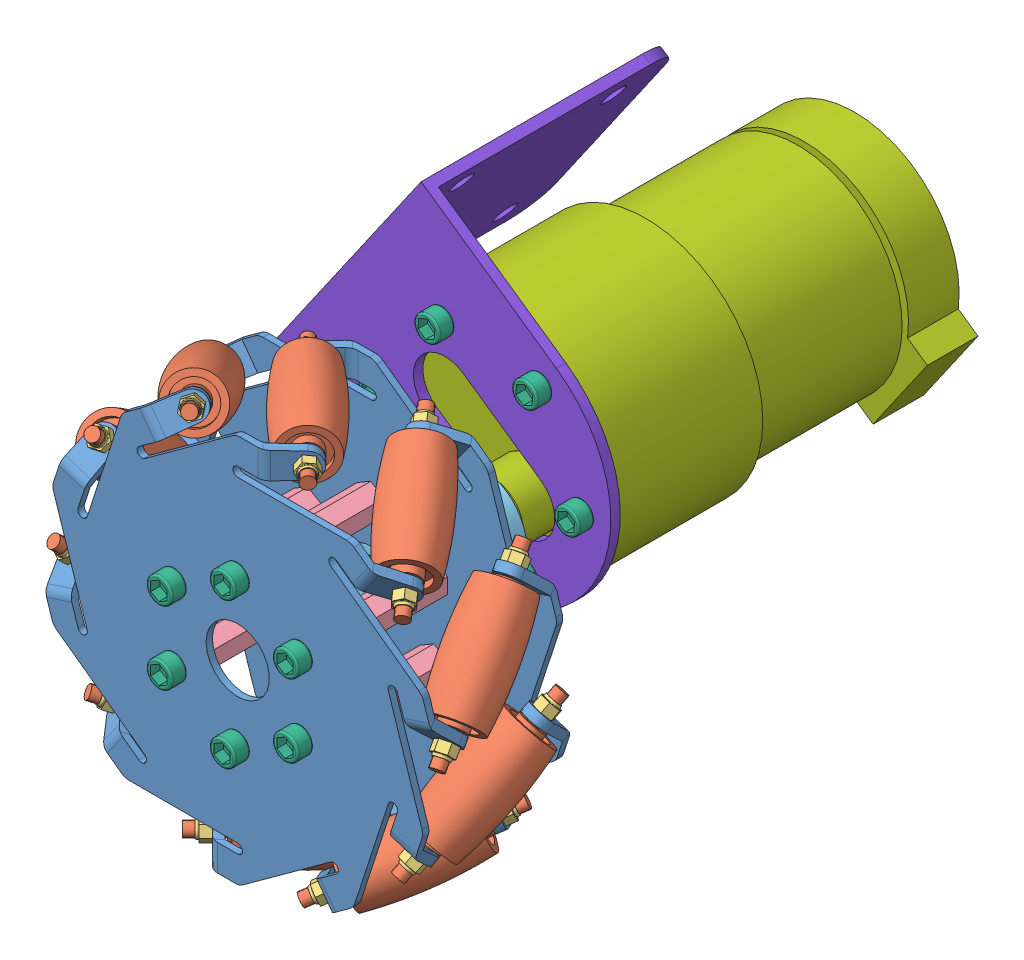
SolidWorks assembly 左前轮, configuration 默认. Lengths in mm.
Overall size (75.09 69.56 106.55).
61 component instances, 8 part files, 9 mates.
Components (placement in the parent):
- 麦克纳姆轮装配（2）-1: 麦克纳姆轮装配（2） [默认] at (10.9105 -1.19 -0.8307) size (73.19 68.37 28.98)
  - 麦克纳姆轮（2）-1: 麦克纳姆轮（2） [默认] at (4.7846 1.1432 62.959) size (62.96 61.4 5.95)
  - 麦克纳姆轮（2）-2: 麦克纳姆轮（2） [默认] at (4.7846 1.1432 85.0986) x (-1 0 0) z (0 0 -1) size (62.96 61.4 5.95)
  - 辊子-1: 辊子 [默认] at (-6.5323 29.7426 62.712) x (0.707107 0 0.707107) z (-0.707107 0 0.707107) size (28 9.23 9.23)
  - 辊子-2: 辊子 [默认] at (-21.1917 17.6211 62.6991) x (0.572061 0.415627 0.707107) z (-0.707107 -0.186947 0.681946) size (28 9.23 9.23)
  - 辊子-3: 辊子 [默认] at (-25.9161 -0.7943 62.6991) x (0.218508 0.672499 0.707107) z (-0.650722 -0.439573 0.619142) size (28 9.23 9.23)
  - 辊子-4: 辊子 [默认] at (-25.9121 3.0685 85.3457) x (0.218508 -0.672499 -0.707107) z (0.395342 -0.60148 0.694209) size (28 9.23 9.23)
  - 辊子-6: 辊子 [默认] at (-21.1812 -15.3423 85.3457) x (0.572061 -0.415627 -0.707107) z (0.647393 -0.300533 0.700401) size (28 9.23 9.23)
  - 辊子-7: 辊子 [默认] at (-6.5323 -27.4561 85.3457) x (0.707107 0 -0.707107) z (0.705301 0.071414 0.705301) size (28 9.23 9.23)
  - 辊子-8: 辊子 [默认] at (12.4393 -28.646 85.3457) x (0.572061 0.415627 -0.707107) z (0.714443 0.170963 0.678486) size (28 9.23 9.23)
  - 辊子-9: 辊子 [默认] at (35.4853 3.0808 62.6991) x (-0.218508 -0.672499 0.707107) z (-0.954109 -0.00482 -0.29942) size (28 9.23 9.23)
  - 辊子-10: 辊子 [默认] at (28.4831 20.7562 62.6991) x (0.218508 -0.672499 0.707107) z (-0.771684 0.324444 0.547028) size (28 9.23 9.23)
  - 辊子-11: 辊子 [默认] at (12.4289 30.9401 62.6991) x (0.572061 -0.415627 0.707107) z (-0.689 0.22422 0.689206) size (28 9.23 9.23)
  - M2【螺母】-1: M2【螺母】 [默认] at (-5.0722 29.3326 82.6238) x (0.808299 -0.139279 -0.572061) z (-0.572061 -0.415627 -0.707107) size (2.79 3.22 1.95)
  - M2【螺母】-2: M2【螺母】 [默认] at (13.3795 29.7426 82.6238) x (0.572061 -0.587785 -0.572061) z (-0.707107 0 -0.707107) size (2.79 3.22 1.95)
  - M2【螺母】-3: M2【螺母】 [默认] at (28.5483 19.2286 82.6238) x (0.117316 -0.811778 -0.572061) z (-0.572061 0.415627 -0.707107) size (2.79 3.22 1.95)
  - M2【螺母】-4: M2【螺母】 [默认] at (34.6402 1.8066 82.6238) x (-0.38224 -0.725698 -0.572061) z (-0.218508 0.672499 -0.707107) size (2.79 3.22 1.95)
  - M2【螺母】-5: M2【螺母】 [默认] at (29.3282 -15.8687 82.6238) x (-0.735794 -0.362427 -0.572061) z (0.218508 0.672499 -0.707107) size (2.79 3.22 1.95)
  - M2【螺母】-6: M2【螺母】 [默认] at (14.6414 -27.0461 82.6238) x (-0.808299 0.139279 -0.572061) z (0.572061 0.415627 -0.707107) size (2.79 3.22 1.95)
  - M2【螺母】-7: M2【螺母】 [默认] at (-3.8104 -27.4561 82.6238) x (-0.572061 0.587785 -0.572061) z (0.707107 0 -0.707107) size (2.79 3.22 1.95)
  - M2【螺母】-8: M2【螺母】 [默认] at (-18.9791 -16.9422 82.6238) x (-0.117316 0.811778 -0.572061) z (0.572061 -0.415627 -0.707107) size (2.79 3.22 1.95)
  - M2【螺母】-9: M2【螺母】 [默认] at (-25.071 0.4798 82.6238) x (0.38224 0.725698 -0.572061) z (0.218508 -0.672499 -0.707107) size (2.79 3.22 1.95)
  - M2【螺母】-10: M2【螺母】 [默认] at (-19.759 18.1552 82.6238) x (0.735794 0.362427 -0.572061) z (-0.218508 -0.672499 -0.707107) size (2.79 3.22 1.95)
  - M2【螺母】-11: M2【螺母】 [默认] at (-19.759 -15.8687 65.4339) x (0.972031 0.086079 0.218508) z (-0.218508 0.672499 0.707107) size (2.79 3.22 1.95)
  - M2【螺母】-12: M2【螺母】 [默认] at (-5.0722 -27.0461 65.4339) x (0.735794 0.640985 0.218508) z (-0.572061 0.415627 0.707107) size (2.79 3.22 1.95)
  - M2【螺母】-13: M2【螺母】 [默认] at (13.3795 -27.4561 65.4339) x (0.218508 0.951057 0.218508) z (-0.707107 0 0.707107) size (2.79 3.22 1.95)
  - M2【螺母】-14: M2【螺母】 [默认] at (28.5483 -16.9422 65.4339) x (-0.38224 0.897857 0.218508) z (-0.572061 -0.415627 0.707107) size (2.79 3.22 1.95)
  - M2【螺母】-15: M2【螺母】 [默认] at (34.6402 0.4798 65.4339) x (-0.836986 0.501706 0.218508) z (-0.218508 -0.672499 0.707107) size (2.79 3.22 1.95)
  - M2【螺母】-16: M2【螺母】 [默认] at (29.3282 18.1552 65.4339) x (-0.972031 -0.086079 0.218508) z (0.218508 -0.672499 0.707107) size (2.79 3.22 1.95)
  - M2【螺母】-17: M2【螺母】 [默认] at (14.6414 29.3326 65.4339) x (-0.735794 -0.640985 0.218508) z (0.572061 -0.415627 0.707107) size (2.79 3.22 1.95)
  - M2【螺母】-18: M2【螺母】 [默认] at (-3.8104 29.7426 65.4339) x (-0.218508 -0.951057 0.218508) z (0.707107 0 0.707107) size (2.79 3.22 1.95)
  - M2【螺母】-19: M2【螺母】 [默认] at (-18.9791 19.2286 65.4339) x (0.38224 -0.897857 0.218508) z (0.572061 0.415627 0.707107) size (2.79 3.22 1.95)
  - M2【螺母】-20: M2【螺母】 [默认] at (-25.071 1.8066 65.4339) x (0.836986 -0.501706 0.218508) z (0.218508 0.672499 0.707107) size (2.79 3.22 1.95)
  - 20mm长-M3【六角铜柱】-1: 20mm长-M3【六角铜柱】 [默认] at (14.7439 -4.6068 64.0986) size (4.27 4.93 20)
  - 20mm长-M3【六角铜柱】-2: 20mm长-M3【六角铜柱】 [默认] at (4.7846 -10.3568 64.0986) x (0.5 -0.866025 0) z (0 0 1) size (4.27 4.93 20)
  - 20mm长-M3【六角铜柱】-3: 20mm长-M3【六角铜柱】 [默认] at (-5.1747 -4.6068 64.0986) x (-0.5 -0.866025 0) z (0 0 1) size (4.27 4.93 20)
  - 20mm长-M3【六角铜柱】-4: 20mm长-M3【六角铜柱】 [默认] at (-5.1747 6.8932 64.0986) x (-1 0 0) z (0 0 1) size (4.27 4.93 20)
  - 20mm长-M3【六角铜柱】-5: 20mm长-M3【六角铜柱】 [默认] at (4.7846 12.6432 64.0986) x (-0.5 0.866025 0) z (0 0 1) size (4.27 4.93 20)
  - 20mm长-M3【六角铜柱】-6: 20mm长-M3【六角铜柱】 [默认] at (14.7439 6.8932 64.0986) x (0.5 0.866025 0) z (0 0 1) size (4.27 4.93 20)
- 法兰联轴器-1: 法兰联轴器 [默认] at (15.6951 -0.0468 62.1283) x (1 0 0) z (0 0 -1) size (28 28 16)
- M3-8【内六角螺丝】-1: M3-8【内六角螺丝】 [默认] at (15.6951 11.4532 76.2679) size (4 4 10.5)
- M3-8【内六角螺丝】-2: M3-8【内六角螺丝】 [默认] at (25.6544 5.7032 76.2679) x (0.5 -0.866025 0) z (0 0 1) size (4 4 10.5)
- M3-8【内六角螺丝】-3: M3-8【内六角螺丝】 [默认] at (25.6544 -5.7968 76.2679) x (-0.5 -0.866025 0) z (0 0 1) size (4 4 10.5)
- M3-8【内六角螺丝】-4: M3-8【内六角螺丝】 [默认] at (15.6951 -11.5468 76.2679) x (-1 0 0) z (0 0 1) size (4 4 10.5)
- M3-8【内六角螺丝】-5: M3-8【内六角螺丝】 [默认] at (5.7358 -5.7968 76.2679) x (-0.5 0.866025 0) z (0 0 1) size (4 4 10.5)
- M3-8【内六角螺丝】-6: M3-8【内六角螺丝】 [默认] at (5.7358 5.7032 76.2679) x (0.5 0.866025 0) z (0 0 1) size (4 4 10.5)
- M3-8【内六角螺丝】-7: M3-8【内六角螺丝】 [默认] at (15.6951 11.4532 66.1283) x (1 0 0) z (0 0 -1) size (4 4 10.5)
- M3-8【内六角螺丝】-8: M3-8【内六角螺丝】 [默认] at (25.6544 5.7032 66.1283) x (0.5 -0.866025 0) z (0 0 -1) size (4 4 10.5)
- M3-8【内六角螺丝】-9: M3-8【内六角螺丝】 [默认] at (25.6544 -5.7968 66.1283) x (-0.5 -0.866025 0) z (0 0 -1) size (4 4 10.5)
- M3-8【内六角螺丝】-10: M3-8【内六角螺丝】 [默认] at (15.6951 -11.5468 66.1283) x (-1 0 0) z (0 0 -1) size (4 4 10.5)
- M3-8【内六角螺丝】-11: M3-8【内六角螺丝】 [默认] at (5.7358 -5.7968 66.1283) x (-0.5 0.866025 0) z (0 0 -1) size (4 4 10.5)
- M3-8【内六角螺丝】-12: M3-8【内六角螺丝】 [默认] at (5.7358 5.7032 66.1283) x (0.5 0.866025 0) z (0 0 -1) size (4 4 10.5)
- 电机总装-1: 电机总装 [默认] at (-90.9994 -4.0032 217.8434) x (-0.570597 -0.82123 0) z (0 0 -1) size (40 46 75)
  - 减速比1：10【码盘减速电机】-1: 减速比1：10【码盘减速电机】 [默认] at (-64.1287 -78.3632 203.7151) x (1 0 0) z (0 0 -1) size (37 37 75)
  - 电机支架-2: 电机支架 [默认] at (-64.1287 -78.3632 179.7151) x (1 0 0) z (0 0 -1) size (40 46 40)
  - M3-8【内六角螺丝】-13: M3-8【内六角螺丝】 [默认] at (-56.3787 -64.9398 186.2151) x (-1 0 0) z (0 0 -1) size (4 4 10.5)
  - M3-8【内六角螺丝】-14: M3-8【内六角螺丝】 [默认] at (-71.8787 -64.9398 186.2151) x (-0.5 -0.866025 0) z (0 0 -1) size (4 4 10.5)
  - M3-8【内六角螺丝】-15: M3-8【内六角螺丝】 [默认] at (-79.6287 -78.3632 186.2151) x (0.5 -0.866025 0) z (0 0 -1) size (4 4 10.5)
  - M3-8【内六角螺丝】-16: M3-8【内六角螺丝】 [默认] at (-71.8787 -91.7866 186.2151) x (1 0 0) z (0 0 -1) size (4 4 10.5)
  - M3-8【内六角螺丝】-17: M3-8【内六角螺丝】 [默认] at (-56.3787 -91.7866 186.2151) x (0.5 0.866025 0) z (0 0 -1) size (4 4 10.5)
  - M3-8【内六角螺丝】-18: M3-8【内六角螺丝】 [默认] at (-48.6287 -78.3632 186.2151) x (-0.5 0.866025 0) z (0 0 -1) size (4 4 10.5)
Mates (geometry in assembly coordinates):
- 同心1: concentric: cylinder of assembly; cylinder of assembly; cylinder of 麦克纳姆轮装配（2）-1/麦克纳姆轮（2）-1 through (15.6951 -0.0468 62.1283) axis (0 0 1) radius 5; cylinder of 法兰联轴器-1 through (15.6951 -0.0468 62.1283) axis (0 0 -1) radius 3
- 同心2: concentric: cylinder of assembly; cylinder of assembly; cylinder of 麦克纳姆轮装配（2）-1/麦克纳姆轮（2）-1 through (15.6951 11.4532 62.1283) axis (0 0 1) radius 1.5; cylinder of 法兰联轴器-1 through (15.6951 11.4532 58.1283) axis (0 0 1) radius 1.5
- 重合1: coincident: plane of assembly; plane of assembly; plane of 麦克纳姆轮装配（2）-1/麦克纳姆轮（2）-1 through (15.6951 25.7032 62.1283) normal (0 0 -1); plane of 法兰联轴器-1 through (15.6951 -0.0468 62.1283) normal (0 0 1)
- 同心4: concentric: cylinder of assembly; cylinder of assembly; cylinder of 麦克纳姆轮装配（2）-1/麦克纳姆轮（2）-2 through (15.6951 11.4532 84.2679) axis (0 0 -1) radius 1.5; cylinder of M3-8【内六角螺丝】-1 through (15.6951 11.4532 84.2679) axis (0 0 -1) radius 1.5
- 重合2: coincident: plane of 麦克纳姆轮装配（2）-1/麦克纳姆轮（2）-2 through (15.6951 25.7032 84.2679) normal (0 0 1); plane of M3-8【内六角螺丝】-1 through (15.6951 11.4532 84.2679) normal (0 0 -1)
- 同心5: concentric: cylinder of assembly; cylinder of assembly; cylinder of 法兰联轴器-1 through (15.6951 11.4532 58.1283) axis (0 0 1) radius 1.5; cylinder of M3-8【内六角螺丝】-7 through (15.6951 11.4532 58.1283) axis (0 0 1) radius 1.5
- 重合3: coincident: plane of 法兰联轴器-1 through (15.6951 -0.0468 58.1283) normal (0 0 -1); plane of M3-8【内六角螺丝】-7 through (15.6951 11.4532 58.1283) normal (0 0 1)
- 同心6: concentric: cylinder of 法兰联轴器-1 through (15.6951 -0.0468 62.1283) axis (0 0 -1) radius 3; cylinder of ? through (15.6951 -0.0468 -23.6026) axis (0 0 -1) radius 3
- 距离1: distance = 2 mm: plane of 法兰联轴器-1 through (15.6951 -0.0468 46.1283) normal (0 0 -1); plane of 电机总装-1/减速比1：10【码盘减速电机】-1 through (15.6951 -0.0468 44.1283) normal (0 0 1)
